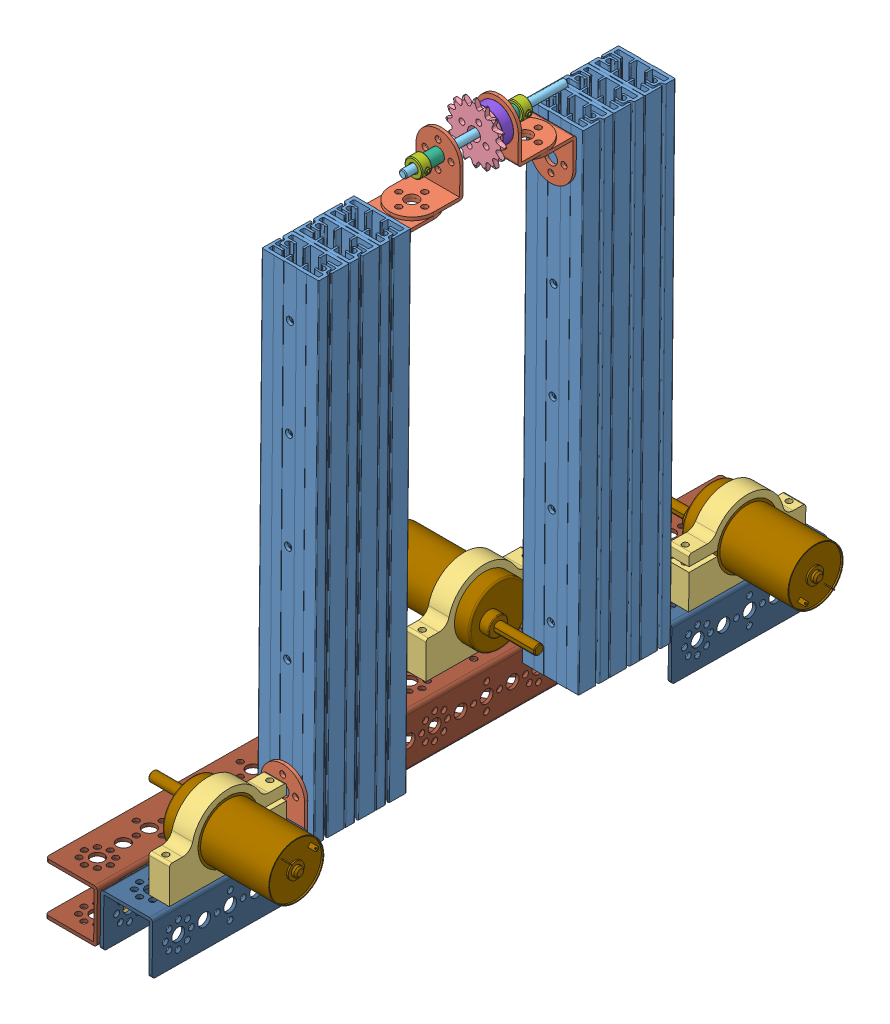
SolidWorks assembly Slide Assembly, configuration Default. Lengths in mm.
Overall size (146.74 363.02 416.27).
30 component instances, 12 part files, 76 mates.
Components (placement in the parent):
- Linear Slide-2: Linear Slide [Default] at (-67.6476 343.203 55.6889) x (1 -0.000714 -0.00007) z (0.000076 0.008726 0.999962) size (35 300 19)
- Linear Slide-3: Linear Slide [Default] at (-67.6462 343.3688 74.6882) x (1 -0.000714 -0.00007) z (0.000076 0.008726 0.999962) size (35 300 19)
- Linear Slide-5: Linear Slide [Default] at (-67.6491 343.0372 36.6897) x (1 -0.000714 -0.00007) z (0.000076 0.008726 0.999962) size (35 300 19)
- Linear Slide-7: Linear Slide [Default] at (-67.6615 341.6148 -126.3041) x (1 -0.000714 -0.00007) z (-0.000076 -0.008726 -0.999962) size (35 300 19)
- Linear Slide-8: Linear Slide [Default] at (-67.66 341.7806 -107.3048) x (1 -0.000714 -0.00007) z (-0.000076 -0.008726 -0.999962) size (35 300 19)
- Linear Slide-10: Linear Slide [Default] at (-67.6586 341.9464 -88.3056) x (1 -0.000714 -0.00007) z (-0.000076 -0.008726 -0.999962) size (35 300 19)
- Tetrix Angle Bracket-5: Tetrix Angle Bracket [Default] at (-66.9961 216.836 -154.7548) x (1 -0.000714 -0.00007) z (0.000076 0.008726 0.999962) size (27 31.5 31.5)
- Tetrix Angle Bracket-6: Tetrix Angle Bracket [Default] at (-68.4891 219.1065 105.3122) x (-1 0.000714 0.00007) z (-0.000076 -0.008726 -0.999962) size (27 31.5 31.5)
- Tetrix Motor Mount-1: Tetrix Motor Mount [Default] at (-53.8009 221.5734 -173.6188) x (-0.000076 -0.008726 -0.999962) z (1 -0.000714 -0.00007) size (72 44.98 12.7)
- Tetrix 16T Sprocket-2: Tetrix 16T Sprocket [Default] at (-67.5374 506.4331 -33.244) x (-0.934323 0.356413 -0.003039) z (-0.000076 -0.008726 -0.999962) size (36 36 6.8)
- Tetrix 4.7mm Axle-2: Tetrix 4.7mm Axle [Default] at (-67.5338 506.8416 13.5594) x (1 -0.000001 -0.000076) z (-0.000076 -0.008726 -0.999962) size (4.7 4.3 100)
- Tetrix 4.7mm Axle Bushing-3: Tetrix 4.7mm Axle Bushing [Default] at (-67.5356 506.6339 -10.2397) x (1 -0.000001 -0.000076) z (-0.000076 -0.008726 -0.999962) size (10.17 10.17 12.4)
- Tetrix 4.7mm Axle collar-3: Tetrix 4.7mm Axle collar [Default] at (-67.3521 506.6078 -58.5375) x (1 -0.000001 -0.000076) z (-0.000076 -0.008726 -0.999962) size (11.66 11 6.2)
- Tetrix 4.7mm Axle Hub-2: Tetrix 4.7mm Axle Hub [Default] at (-67.5377 506.3982 -37.2439) x (-0.729969 -0.683453 0.00602) z (0.000076 0.008726 0.999962) size (22 22 9.4)
- Tetrix Angle Bracket-7: Tetrix Angle Bracket [Default] at (-66.7808 509.6363 -64.3064) x (1 -0.000714 -0.00007) z (0.000076 0.008726 0.999962) size (27 31.5 31.5)
- Tetrix Angle Bracket-8: Tetrix Angle Bracket [Default] at (-68.319 467.3006 6.0658) x (-1 0.000714 0.00007) z (0.000076 0.008726 0.999962) size (27 31.5 31.5)
- Tetrix Angle Bracket-9: Tetrix Angle Bracket [Default] at (-68.2881 510.2838 9.7677) x (-1 0.000714 0.00007) z (-0.000076 -0.008726 -0.999962) size (27 31.5 31.5)
- Tetrix Angle Bracket-10: Tetrix Angle Bracket [Default] at (-66.8111 466.7242 -59.855) x (1 -0.000714 -0.00007) z (-0.000076 -0.008726 -0.999962) size (27 31.5 31.5)
- Tetrix 4.7mm Axle Bushing-4: Tetrix 4.7mm Axle Bushing [Default] at (-67.5382 506.3372 -44.2384) x (0.923728 -0.383035 0.003272) z (0.000076 0.008726 0.999962) size (10.17 10.17 12.4)
- Tetrix 4.7mm Axle collar-4: Tetrix 4.7mm Axle collar [Default] at (-67.3474 507.1505 3.6601) x (1 -0.000001 -0.000076) z (-0.000076 -0.008726 -0.999962) size (11.66 11 6.2)
- Tetrix Motor Mount-3: Tetrix Motor Mount [Default] at (-65.6773 224.1798 124.0893) x (0.000076 0.008726 0.999962) z (-1 0.000714 0.00007) size (72 44.98 12.7)
- Tetrix Motor-1: Tetrix Motor [Default] at (-53.3768 224.3824 135.2277) x (0.000713 0.999962 -0.008727) z (0.000076 0.008726 0.999962) size (37 98.8 37)
- Tetrix Motor-2: Tetrix Motor [Default] at (-53.4012 221.59 -184.7601) x (-0.000713 -0.999962 0.008727) z (-0.000076 -0.008727 -0.999962) size (37 98.8 37)
- Tetrix 96mm-1: Tetrix 96mm [Default] at (-67.775 183.5206 -136.4249) x (1 -0.000714 -0.00007) z (0.000076 0.008726 0.999962) size (32 32 96)
- Tetrix 96mm-2: Tetrix 96mm [Default] at (-67.7506 186.3129 183.5629) x (1 -0.000714 -0.00007) z (0.000076 0.008726 0.999962) size (32 32 96)
- Tetrix 416mm-1: Tetrix 416mm [Default] at (-101.7506 186.3372 183.5653) x (-0.000713 -0.999962 0.008726) z (0.000076 0.008726 0.999962) size (32 32 416)
- Bracket flat-1: Bracket flat [Default] at (-84.7786 183.1138 -184.4219) x (-0.000076 -0.008726 -0.999962) z (-0.000713 -0.999962 0.008726) size (91 2 27)
- Bracket flat-2: Bracket flat [Default] at (-84.7543 185.9062 135.5659) x (-0.000076 -0.008726 -0.999962) z (-0.000713 -0.999962 0.008726) size (91 2 27)
- Tetrix Motor Mount-6: Tetrix Motor Mount [Default] at (-107.692 223.1246 -75.9059) x (0.000076 0.008726 0.999962) z (-1 0.000714 0.00007) size (72 44.98 12.7)
- Tetrix Motor-5: Tetrix Motor [Default] at (-108.0916 223.3362 -64.7666) x (0.000713 0.999962 -0.008726) z (-0.000076 -0.008726 -0.999962) size (37 98.8 37)
Mates (geometry in assembly coordinates):
- Coincident5: coincident anti-aligned: plane of Linear Slide-2 through (-71.7538 193.2945 66.4978) normal (0.000076 0.008726 0.999962); plane of Linear Slide-3 through (-77.7538 193.2988 66.4982) normal (-0.000076 -0.008726 -0.999962)
- Coincident6: coincident aligned: plane of Linear Slide-2 through (-50.2543 193.2303 60.8965) normal (1 -0.000714 -0.00007); plane of Linear Slide-3 through (-50.2528 193.3961 79.8958) normal (1 -0.000714 -0.00007)
- Coincident7: coincident aligned: plane of Linear Slide-2 through (-67.8475 493.1488 48.8032) normal (0.000713 0.999962 -0.008726); plane of Linear Slide-3 through (-67.846 493.3146 67.8025) normal (0.000713 0.999962 -0.008726)
- Coincident14: coincident anti-aligned: plane of Linear Slide-7 through (-63.5538 491.6891 -118.1137) normal (0.000076 0.008726 0.999962); plane of Linear Slide-8 through (-57.5538 491.6849 -118.1141) normal (-0.000076 -0.008726 -0.999962)
- Coincident15: coincident aligned: plane of Linear Slide-7 through (-85.0552 491.5439 -136.5115) normal (-1 0.000714 0.00007); plane of Linear Slide-8 through (-85.0538 491.7097 -117.5122) normal (-1 0.000714 0.00007)
- Coincident16: coincident aligned: plane of Linear Slide-7 through (-68.0743 191.6695 -119.4183) normal (-0.000713 -0.999962 0.008726); plane of Linear Slide-8 through (-68.0729 191.8353 -100.4191) normal (-0.000713 -0.999962 0.008726)
- Coincident37: coincident anti-aligned: plane of Linear Slide-3 through (-57.7524 193.4503 85.4961) normal (0.000076 0.008726 0.999962); plane of Tetrix Angle Bracket-6 through (-54.2271 228.9465 85.1861) normal (-0.000076 -0.008726 -0.999962)
- Parallel1: parallel aligned: plane of Linear Slide-3 through (-67.4463 193.423 81.574) normal (-0.000713 -0.999962 0.008726); plane of Tetrix Angle Bracket-6 through (-54.2495 197.4477 85.461) normal (-0.000713 -0.999962 0.008726)
- Parallel2: parallel anti-aligned: plane of Linear Slide-3 through (-63.7524 193.4529 85.2965) normal (0.000076 0.008726 0.999962); plane of Tetrix Angle Bracket-6 through (-54.2271 228.9465 85.1861) normal (-0.000076 -0.008726 -0.999962)
- Concentric20: concentric aligned: cylinder of Linear Slide-3 through (-67.7317 223.3734 75.7354) axis (-0.000076 -0.008726 -0.999962) radius 2.25; cylinder of Tetrix Angle Bracket-6 through (-67.7286 223.7312 116.7338) axis (-0.000076 -0.008726 -0.999962) radius 1.85
- Coincident54: coincident aligned: plane of Linear Slide-5 through (-67.2354 493.0799 40.9575) normal (0.000713 0.999962 -0.008726); plane of Linear Slide-10 through (-67.8576 491.9896 -84.0377) normal (0.000713 0.999962 -0.008726)
- Coincident55: coincident: line of Linear Slide-10 through (-77.5509 492.0307 -80.1142) axis (-0.000713 -0.999962 0.008726); plane of Tetrix Angle Bracket-10 through (-81.0762 456.5346 -79.8041) normal (-0.000076 -0.008726 -0.999962)
- Concentric35: concentric aligned: cylinder of Linear Slide-10 through (-67.573 461.9418 -89.3527) axis (-0.000076 -0.008726 -0.999962) radius 2.25; cylinder of Tetrix Angle Bracket-10 through (-67.5699 462.2996 -48.3543) axis (-0.000076 -0.008726 -0.999962) radius 1.85
- Parallel5: parallel aligned: plane of Linear Slide-10 through (-67.8576 491.9896 -84.0377) normal (0.000713 0.999962 -0.008726); plane of Tetrix Angle Bracket-10 through (-81.0538 488.0334 -80.079) normal (0.000713 0.999962 -0.008726)
- Coincident58: coincident anti-aligned: plane of Linear Slide-5 through (-63.7567 192.9572 28.4987) normal (-0.000076 -0.008726 -0.999962); plane of Tetrix Angle Bracket-8 through (-54.0682 457.4403 26.1899) normal (0.000076 0.008726 0.999962)
- Concentric36: concentric aligned: cylinder of Linear Slide-5 through (-67.5635 463.0326 35.6425) axis (0.000076 0.008726 0.999962) radius 2.25; cylinder of Tetrix Angle Bracket-8 through (-67.5666 462.6748 -5.3559) axis (0.000076 0.008726 0.999962) radius 1.85
- Coincident59: coincident aligned: plane of Tetrix Angle Bracket-8 through (-54.0457 488.9391 25.9151) normal (0.000713 0.999962 -0.008726); plane of Tetrix Angle Bracket-10 through (-81.0538 488.0334 -80.079) normal (0.000713 0.999962 -0.008726)
- Parallel6: parallel aligned: plane of Linear Slide-5 through (-67.8489 492.983 29.8039) normal (0.000713 0.999962 -0.008726); plane of Tetrix Angle Bracket-8 through (-54.0457 488.9391 25.9151) normal (0.000713 0.999962 -0.008726)
- Coincident61: coincident anti-aligned: plane of Tetrix Angle Bracket-8 through (-54.0457 488.9391 25.9151) normal (0.000713 0.999962 -0.008726); plane of Tetrix Angle Bracket-9 through (-54.0485 488.6249 -10.0836) normal (-0.000713 -0.999962 0.008726)
- Concentric37: concentric anti-aligned: cylinder of Tetrix Angle Bracket-8 through (-67.5695 457.2929 8.1916) axis (0.000713 0.999962 -0.008726) radius 4; cylinder of Tetrix Angle Bracket-9 through (-67.5246 520.2904 7.6418) axis (-0.000713 -0.999962 0.008726) radius 4
- Concentric38: concentric anti-aligned: cylinder of Tetrix Angle Bracket-8 through (-67.5689 457.3627 16.1913) axis (0.000713 0.999962 -0.008726) radius 1.85; cylinder of Tetrix Angle Bracket-9 through (-67.524 520.3603 15.6415) axis (-0.000713 -0.999962 0.008726) radius 1.85
- Coincident62: coincident anti-aligned: plane of Tetrix Angle Bracket-7 through (-81.051 488.3475 -44.0804) normal (-0.000713 -0.999962 0.008726); plane of Tetrix Angle Bracket-10 through (-81.0538 488.0334 -80.079) normal (0.000713 0.999962 -0.008726)
- Concentric39: concentric anti-aligned: cylinder of Tetrix Angle Bracket-7 through (-67.53 519.6796 -62.3555) axis (-0.000713 -0.999962 0.008726) radius 4; cylinder of Tetrix Angle Bracket-10 through (-67.5749 456.682 -61.8058) axis (0.000713 0.999962 -0.008726) radius 4
- Concentric40: concentric anti-aligned: cylinder of Tetrix Angle Bracket-7 through (-67.5293 519.7494 -54.3558) axis (-0.000713 -0.999962 0.008726) radius 1.85; cylinder of Tetrix Angle Bracket-10 through (-67.5743 456.7518 -53.8061) axis (0.000713 0.999962 -0.008726) radius 1.85
- Concentric41: concentric aligned: cylinder of Tetrix 4.7mm Axle Bushing-3 through (-67.5348 506.7299 0.7599) axis (-0.000076 -0.008726 -0.999962) radius 3.925; cylinder of Tetrix Angle Bracket-9 through (-67.5332 506.9088 21.2591) axis (-0.000076 -0.008726 -0.999962) radius 4
- Coincident63: coincident anti-aligned: plane of Tetrix 4.7mm Axle Bushing-3 through (-67.5356 506.6339 -10.2397) normal (0.000076 0.008726 0.999962); plane of Tetrix Angle Bracket-9 through (-54.026 520.1237 -10.3585) normal (-0.000076 -0.008726 -0.999962)
- Concentric42: concentric aligned: cylinder of Tetrix Angle Bracket-7 through (-67.5406 506.0623 -75.7372) axis (0.000076 0.008726 0.999962) radius 4; cylinder of Tetrix 4.7mm Axle Bushing-4 through (-67.539 506.2412 -55.238) axis (0.000076 0.008726 0.999962) radius 3.925
- Coincident64: coincident anti-aligned: plane of Tetrix Angle Bracket-7 through (-81.0286 519.8463 -44.3553) normal (0.000076 0.008726 0.999962); plane of Tetrix 4.7mm Axle Bushing-4 through (-67.5382 506.3372 -44.2384) normal (-0.000076 -0.008726 -0.999962)
- Concentric43: concentric anti-aligned: cylinder of Tetrix 4.7mm Axle-2 through (-67.5414 505.969 -86.4368) axis (0.000076 0.008726 0.999962) radius 2.35; cylinder of Tetrix 4.7mm Axle Bushing-3 through (-67.5348 506.7299 0.7599) axis (-0.000076 -0.008726 -0.999962) radius 2.4
- Concentric44: concentric anti-aligned: cylinder of Tetrix 4.7mm Axle-2 through (-67.5414 505.969 -86.4368) axis (0.000076 0.008726 0.999962) radius 2.35; cylinder of Tetrix 4.7mm Axle collar-3 through (-67.539 506.2412 -55.238) axis (-0.000076 -0.008726 -0.999962) radius 2.425
- Coincident65: coincident anti-aligned: circle of Tetrix 4.7mm Axle collar-3; plane of Tetrix 4.7mm Axle Bushing-4 through (-67.539 506.2412 -55.238) normal (-0.000076 -0.008726 -0.999962)
- Coincident66: coincident anti-aligned: plane of Tetrix 4.7mm Axle Bushing-3 through (-67.5348 506.7299 0.7599) normal (0.000076 0.008726 0.999962); plane of Tetrix 4.7mm Axle collar-4 through (-67.5348 506.7299 0.7599) normal (-0.000076 -0.008726 -0.999962)
- Concentric45: concentric anti-aligned: cylinder of Tetrix 4.7mm Axle-2 through (-67.5414 505.969 -86.4368) axis (0.000076 0.008726 0.999962) radius 2.35; cylinder of Tetrix 4.7mm Axle collar-4 through (-67.5343 506.784 6.9596) axis (-0.000076 -0.008726 -0.999962) radius 2.425
- Concentric46: concentric aligned: cylinder of Tetrix 4.7mm Axle-2 through (-67.5414 505.969 -86.4368) axis (0.000076 0.008726 0.999962) radius 2.35; cylinder of Tetrix 4.7mm Axle Hub-2 through (-67.5382 506.3398 -43.9436) axis (0.000076 0.008726 0.999962) radius 2.365
- Coincident68: coincident anti-aligned: plane of Linear Slide-7 through (-57.5553 491.5191 -137.1134) normal (-0.000076 -0.008726 -0.999962); plane of Tetrix Angle Bracket-5 through (-81.2438 227.046 -134.8037) normal (0.000076 0.008726 0.999962)
- Concentric49: concentric aligned: cylinder of Linear Slide-7 through (-67.747 221.6194 -125.257) axis (0.000076 0.008726 0.999962) radius 2.25; cylinder of Tetrix Angle Bracket-5 through (-67.7501 221.2617 -166.2554) axis (0.000076 0.008726 0.999962) radius 1.85
- Concentric58: concentric anti-aligned: cylinder of Tetrix Motor-1 through (-8.8768 224.3506 135.2246) axis (1 -0.000714 -0.00007) radius 17; cylinder of Tetrix Motor Mount-3 through (-53.3768 224.3824 135.2277) axis (-1 0.000714 0.00007) radius 18.5
- Concentric59: concentric aligned: cylinder of Tetrix Motor Mount-1 through (-66.1012 221.599 -184.7592) axis (1 -0.000714 -0.00007) radius 18.5; cylinder of Tetrix Motor-2 through (-8.9012 221.5582 -184.7632) axis (1 -0.000714 -0.00007) radius 17
- Coincident73: coincident anti-aligned: plane of Tetrix Angle Bracket-5 through (-81.2673 197.2722 -166.045) normal (0.000713 0.999962 -0.008726); plane of Tetrix 96mm-1 through (-81.7723 196.6923 -232.5425) normal (-0.000713 -0.999962 0.008726)
- Concentric60: concentric anti-aligned: cylinder of Tetrix Angle Bracket-5 through (-67.7452 226.8793 -152.8039) axis (-0.000713 -0.999962 0.008726) radius 4; cylinder of Tetrix 96mm-1 through (-67.7876 167.3815 -152.2847) axis (0.000713 0.999962 -0.008726) radius 4
- Concentric61: concentric anti-aligned: cylinder of Tetrix Angle Bracket-5 through (-59.7452 226.8736 -152.8045) axis (-0.000713 -0.999962 0.008726) radius 1.85; cylinder of Tetrix 96mm-1 through (-59.7876 167.3758 -152.2853) axis (0.000713 0.999962 -0.008726) radius 1.85
- Concentric62: concentric anti-aligned: cylinder of Tetrix Angle Bracket-5 through (-59.7452 226.8736 -152.8045) axis (-0.000713 -0.999962 0.008726) radius 1.85; cylinder of Tetrix Motor Mount-1 through (-59.7648 199.3746 -152.5645) axis (0.000713 0.999962 -0.008726) radius 1.85
- Concentric63: concentric aligned: cylinder of Tetrix Motor Mount-1 through (-59.7697 198.8161 -216.5621) axis (0.000713 0.999962 -0.008726) radius 1.85; cylinder of Tetrix 96mm-1 through (-59.7925 166.8174 -216.2828) axis (0.000713 0.999962 -0.008726) radius 1.85
- Coincident74: coincident anti-aligned: plane of Tetrix Motor Mount-1 through (-66.1145 199.414 -148.5642) normal (-0.000713 -0.999962 0.008726); plane of Tetrix 96mm-1 through (-83.7709 198.6936 -232.5598) normal (0.000713 0.999962 -0.008726)
- Coincident75: coincident anti-aligned: plane of Tetrix Angle Bracket-6 through (-54.2457 199.7225 116.9423) normal (0.000713 0.999962 -0.008726); plane of Tetrix 96mm-2 through (-81.7479 199.4847 87.4453) normal (-0.000713 -0.999962 0.008726)
- Concentric64: concentric anti-aligned: cylinder of Tetrix Angle Bracket-6 through (-67.7257 229.1132 103.1863) axis (-0.000713 -0.999962 0.008726) radius 4; cylinder of Tetrix 96mm-2 through (-67.7681 169.6155 103.7055) axis (0.000713 0.999962 -0.008726) radius 4
- Concentric65: concentric anti-aligned: cylinder of Tetrix Angle Bracket-6 through (-67.7251 229.183 111.186) axis (-0.000713 -0.999962 0.008726) radius 1.85; cylinder of Tetrix 96mm-2 through (-67.7675 169.6853 111.7052) axis (0.000713 0.999962 -0.008726) radius 1.85
- Coincident76: coincident anti-aligned: plane of Tetrix Motor Mount-3 through (-53.3956 201.5691 99.4255) normal (-0.000713 -0.999962 0.008726); plane of Tetrix 96mm-2 through (-83.7465 201.486 87.428) normal (0.000713 0.999962 -0.008726)
- Coincident77: coincident anti-aligned: plane of Linear Slide-8 through (-77.5524 491.8649 -99.1134) normal (0.000076 0.008726 0.999962); plane of Linear Slide-10 through (-71.5524 491.8606 -99.1139) normal (-0.000076 -0.008726 -0.999962)
- Coincident78: coincident aligned: plane of Linear Slide-8 through (-67.859 491.8238 -103.0369) normal (0.000713 0.999962 -0.008726); plane of Linear Slide-10 through (-67.2457 491.8918 -95.1914) normal (0.000713 0.999962 -0.008726)
- Coincident79: coincident aligned: plane of Linear Slide-8 through (-85.0528 491.8214 -104.7127) normal (-1 0.000714 0.00007); plane of Linear Slide-10 through (-85.0523 491.8755 -98.5129) normal (-1 0.000714 0.00007)
- Coincident80: coincident aligned: plane of Linear Slide-2 through (-67.8475 493.1488 48.8032) normal (0.000713 0.999962 -0.008726); plane of Linear Slide-5 through (-67.2354 493.0799 40.9575) normal (0.000713 0.999962 -0.008726)
- Coincident81: coincident anti-aligned: plane of Linear Slide-2 through (-77.7553 193.133 47.4989) normal (-0.000076 -0.008726 -0.999962); plane of Linear Slide-5 through (-71.7553 193.1287 47.4985) normal (0.000076 0.008726 0.999962)
- Coincident82: coincident aligned: plane of Linear Slide-2 through (-85.2548 193.1872 53.0993) normal (-1 0.000714 0.00007); plane of Linear Slide-5 through (-85.2553 193.1331 46.8995) normal (-1 0.000714 0.00007)
- Concentric66: concentric aligned: cylinder of Tetrix Motor Mount-3 through (-59.7453 201.6085 103.4257) axis (0.000713 0.999962 -0.008726) radius 1.85; cylinder of Tetrix 96mm-2 through (-59.7681 169.6097 103.705) axis (0.000713 0.999962 -0.008726) radius 1.85
- Concentric67: concentric aligned: cylinder of Tetrix Motor Mount-3 through (-59.7404 202.167 167.4233) axis (0.000713 0.999962 -0.008726) radius 1.85; cylinder of Tetrix 96mm-2 through (-59.7632 170.1682 167.7025) axis (0.000713 0.999962 -0.008726) radius 1.85
- Concentric68: concentric aligned: cylinder of Tetrix 4.7mm Axle-2 through (-67.5414 505.969 -86.4368) axis (0.000076 0.008726 0.999962) radius 2.35; cylinder of Tetrix 4.7mm Axle Bushing-4 through (-67.539 506.2412 -55.238) axis (0.000076 0.008726 0.999962) radius 2.4
- Distance1: distance = 25 mm aligned: plane of Tetrix 4.7mm Axle collar-3 through (-67.5395 506.1871 -61.4378) normal (-0.000076 -0.008726 -0.999962); plane of Tetrix 4.7mm Axle-2 through (-67.5414 505.969 -86.4368) normal (-0.000076 -0.008726 -0.999962)
- Coincident85: coincident anti-aligned: plane of Tetrix 16T Sprocket-2 through (-67.5377 506.3982 -37.2439) normal (-0.000076 -0.008726 -0.999962); plane of Tetrix 4.7mm Axle Hub-2 through (-67.5377 506.3982 -37.2439) normal (0.000076 0.008726 0.999962)
- Concentric70: concentric aligned: cylinder of Tetrix 16T Sprocket-2 through (-67.5372 506.4576 -30.4441) axis (-0.000076 -0.008726 -0.999962) radius 4; cylinder of Tetrix 4.7mm Axle Hub-2 through (-67.5375 506.4218 -34.544) axis (-0.000076 -0.008726 -0.999962) radius 3.9625
- Coincident91: coincident aligned: plane of Tetrix Motor Mount-1 through (-53.4012 221.59 -184.7601) normal (1 -0.000714 -0.00007); plane of Tetrix Motor-2 through (-53.4133 204.5906 -184.6117) normal (1 -0.000714 -0.00007)
- Coincident92: coincident aligned: plane of Tetrix Motor Mount-3 through (-53.3768 224.3824 135.2277) normal (1 -0.000714 -0.00007); plane of Tetrix Motor-1 through (-53.3647 241.3817 135.0794) normal (1 -0.000714 -0.00007)
- Coincident100: coincident anti-aligned: plane of Tetrix 96mm-1 through (-83.7709 198.6936 -232.5598) normal (-1 0.000714 0.00007); plane of Bracket flat-1 through (-83.7656 197.0096 -139.0415) normal (1 -0.000714 -0.00007)
- Concentric75: concentric aligned: cylinder of Tetrix 96mm-1 through (-83.7762 183.3923 -152.4232) axis (1 -0.000714 -0.00007) radius 4; cylinder of Bracket flat-1 through (-85.7762 183.3938 -152.4231) axis (1 -0.000714 -0.00007) radius 4
- Concentric76: concentric aligned: cylinder of Tetrix 96mm-1 through (-83.7811 182.8339 -216.4208) axis (1 -0.000714 -0.00007) radius 4; cylinder of Bracket flat-1 through (-85.7811 182.8353 -216.4206) axis (1 -0.000714 -0.00007) radius 4
- Coincident102: coincident anti-aligned: plane of Tetrix 96mm-2 through (-83.7465 201.486 87.428) normal (-1 0.000714 0.00007); plane of Bracket flat-2 through (-83.7412 199.802 180.9463) normal (1 -0.000714 -0.00007)
- Concentric78: concentric aligned: cylinder of Tetrix 96mm-2 through (-83.7518 186.1847 167.5646) axis (1 -0.000714 -0.00007) radius 4; cylinder of Bracket flat-2 through (-85.7518 186.1862 167.5647) axis (1 -0.000714 -0.00007) radius 4
- Concentric79: concentric aligned: cylinder of Tetrix 96mm-2 through (-83.7567 185.6263 103.567) axis (1 -0.000714 -0.00007) radius 4; cylinder of Bracket flat-2 through (-85.7567 185.6277 103.5672) axis (1 -0.000714 -0.00007) radius 4
- Concentric88: concentric aligned: cylinder of Tetrix 416mm-1 through (-117.7811 182.8581 -216.4184) axis (1 -0.000714 -0.00007) radius 4; cylinder of Bracket flat-1 through (-85.7811 182.8353 -216.4206) axis (1 -0.000714 -0.00007) radius 4
- Coincident111: coincident anti-aligned: plane of Tetrix 416mm-1 through (-85.7709 198.6951 -232.5596) normal (1 -0.000714 -0.00007); plane of Bracket flat-1 through (-85.7656 197.0111 -139.0414) normal (-1 0.000714 0.00007)
- Concentric89: concentric aligned: cylinder of Tetrix 416mm-1 through (-117.7518 186.209 167.567) axis (1 -0.000714 -0.00007) radius 4; cylinder of Bracket flat-2 through (-85.7518 186.1862 167.5647) axis (1 -0.000714 -0.00007) radius 4
- Concentric118: concentric anti-aligned: cylinder of Tetrix 416mm-1 through (-101.7605 199.8932 -96.5637) axis (-0.000713 -0.999962 0.008726) radius 1.85; cylinder of Tetrix Motor Mount-6 through (-101.7601 200.5533 -96.5695) axis (0.000713 0.999962 -0.008726) radius 1.85
- Concentric119: concentric anti-aligned: cylinder of Tetrix 416mm-1 through (-101.7557 200.4517 -32.5661) axis (-0.000713 -0.999962 0.008726) radius 1.85; cylinder of Tetrix Motor Mount-6 through (-101.7552 201.1118 -32.5719) axis (0.000713 0.999962 -0.008726) radius 1.85
- Concentric120: concentric aligned: cylinder of Tetrix Motor Mount-6 through (-95.3916 223.3271 -64.7675) axis (-1 0.000714 0.00007) radius 18.5; cylinder of Tetrix Motor-5 through (-152.5916 223.3679 -64.7635) axis (-1 0.000714 0.00007) radius 18.5
- Coincident128: coincident aligned: plane of Tetrix Motor Mount-6 through (-108.0916 223.3362 -64.7666) normal (-1 0.000714 0.00007); plane of Tetrix Motor-5 through (-108.0795 240.3355 -64.9149) normal (-1 0.000714 0.00007)
- Parallel12: parallel aligned: plane of Tetrix Motor Mount-6 through (-95.4049 201.1421 -28.5725) normal (0.000076 0.008726 0.999962); plane of Tetrix Motor-5 through (-55.2891 224.4619 -55.4821) normal (0.000076 0.008726 0.999962)
